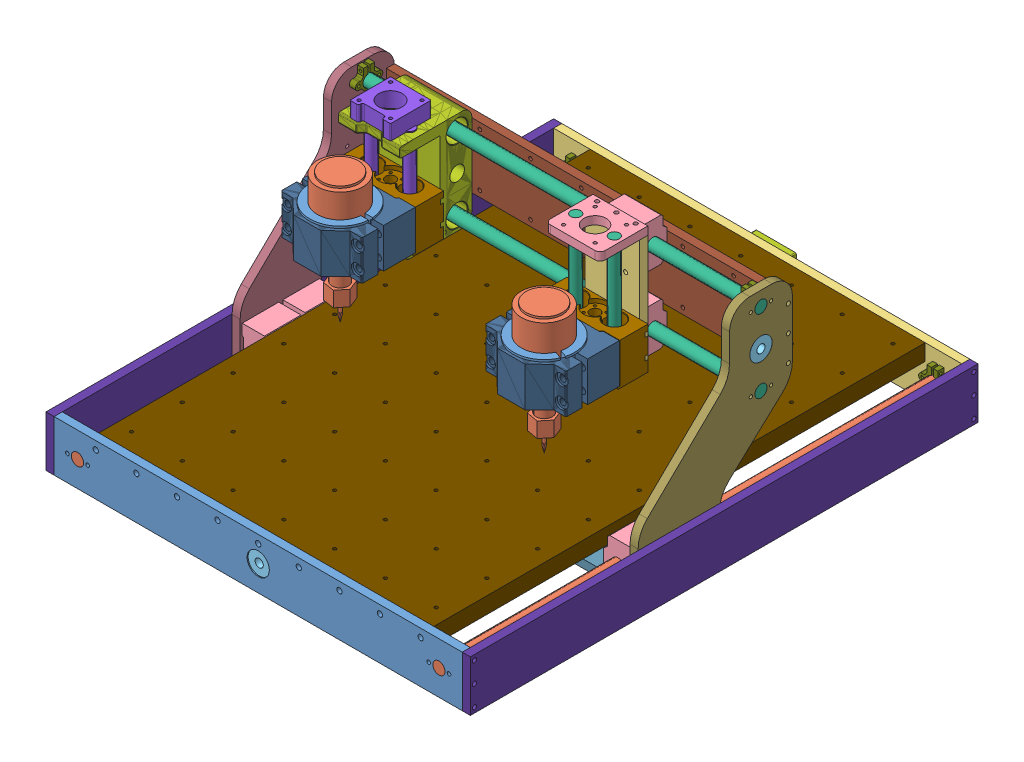
SolidWorks assembly Assem, configuration Default. Lengths in mm.
Overall size (419 226.21 510).
50 component instances, 26 part files, 97 mates.
Components (placement in the parent):
- front-1: front [Default] at (72.2728 169.5305 371.325) size (402 50 8)
- 12x500mm-1: 12x500mm [Default] at (-105.7272 169.5305 -120.675) x (-0.181171 0.983452 0) z (0 0 1) size (12 12 500)
- 12x500mm-2: 12x500mm [Default] at (250.2728 169.5305 -120.675) size (12 12 500)
- back-1: back [Default] at (72.2728 169.5305 -120.675) size (402 50 8)
- scs12uu-1: scs12uu [Default] at (-105.7272 169.5305 167.0973) x (0 -1 0) z (0 0 1) size (42 28 36)
- scs12uu-2: scs12uu [Default] at (250.2728 169.5305 167.0973) x (0 1 0) z (0 0 1) size (42 28 36)
- scs12uu-3: scs12uu [Default] at (-105.7272 169.5305 127.0973) x (0 -1 0) z (0 0 1) size (42 28 36)
- scs12uu-4: scs12uu [Default] at (250.2728 169.5305 127.0973) x (0 1 0) z (0 0 1) size (42 28 36)
- 608zz-1: 608zz [Default] at (72.2728 169.5305 371.325) size (21.9 21.9 7)
- 12x400mm-1: 12x400mm [Default] at (-127.7272 341.1948 84.0973) x (0 0 -1) z (1 0 0) size (12 12 400)
- 12x400mm-2: 12x400mm [Default] at (-127.7272 269.2548 84.0973) x (0 -0.924695 -0.380708) z (1 0 0) size (12 12 400)
- X_Carriage-1: X_Carriage [По умолчанию] at (-27.0136 255.7399 69.5893) x (0 1 0) z (0 0 1) size (100 60 71.3)
- 10x100mm-1: 10x100mm [Default] at (-76.0136 356.7399 119.6893) x (0.002971 0 0.999996) z (0 -1 0) size (10 10 100)
- 10x100mm-2: 10x100mm [Default] at (-38.0136 356.7399 119.6893) x (1 0 0) z (0 -1 0) size (10 10 100)
- Z_Carriage-1: Z_Carriage [По умолчанию] at (-96.2546 270.9801 89.6896) size (80 41 30.36)
- Z_Carriage2-1: Z_Carriage2 [По умолчанию] at (-96.2546 269.4801 89.6646) size (80 39 66.5)
- x_boss-1: x_boss [Default] at (72.2728 304.9298 53.0868) size (384 64 8)
- 608zz-2: 608zz [Default] at (265.2728 305.2248 84.0973) x (0 -0.443087 -0.896479) z (1 0 0) size (21.9 21.9 7)
- right-2: right [Default] at (264.2728 241.8465 141.4627) x (0 0 -1) z (1 0 0) size (152 207.66 8)
- left-2: left [Default] at (-127.7272 241.8563 141.4386) x (0 0 -1) z (1 0 0) size (152 207.66 8)
- y_boss-1: y_boss [Default] at (72.2728 158.2805 165.0973) x (1 0 0) z (0 -1 0) size (336 78 8)
- y_boss2-1: y_boss2 [Default] at (72.2728 177.2805 165.0973) x (1 0 0) z (0 -1 0) size (60 60 19)
- l12mm_holder-1: l12mm_holder [Default] at (-105.7272 169.5305 365.325) size (27 20.92 6)
- l12mm_holder-2: l12mm_holder [Default] at (250.2728 169.5305 365.325) size (27 20.92 6)
- l12mm_holder-3: l12mm_holder [Default] at (250.2728 169.5305 -112.675) size (27 20.92 6)
- l12mm_holder-4: l12mm_holder [Default] at (-105.7272 169.5305 -112.675) size (27 20.92 6)
- l12mm_holder-5: l12mm_holder [Default] at (-119.7272 269.2548 84.0973) x (0 0 -1) z (1 0 0) size (27 20.92 6)
- l12mm_holder-6: l12mm_holder [Default] at (258.2728 341.1948 84.0973) x (0 0 -1) z (1 0 0) size (27 20.92 6)
- l12mm_holder-7: l12mm_holder [Default] at (258.2728 269.2548 84.0973) x (0 0 -1) z (1 0 0) size (27 20.92 6)
- l12mm_holder-8: l12mm_holder [Default] at (-119.7272 341.1948 84.0973) x (0 0 -1) z (1 0 0) size (27 20.92 6)
- side-1: side [Default] at (-136.7272 169.5305 129.325) x (0 0 -1) z (1 0 0) size (500 50 8)
- side-2: side [Default] at (273.2728 169.5305 129.325) x (0 0 -1) z (1 0 0) size (500 50 8)
- table-1: table [Default] at (72.2728 186.5305 -112.675) size (330 16 484)
- 775mot_holder-1: 775mot_holder [Default] at (-57.0136 271.9801 169.2982) x (1 0 0) z (0 1 0) size (59.93 60 37)
- SPINDEL-1: SPINDEL [Default] at (-57.0136 332.6508 169.2982) x (0.999846 0 -0.017553) z (0 -1 0) size (45 45 129)
- Assem1-1: Assem1 [Default] at (58.0268 229.0373 50.2513) size (80 169.79 141.21)
  - Part1-1: Part1 [Default] at (89.8174 75.2675 47.846) size (54 112 8)
  - Part2-1: Part2 [Default] at (89.8174 131.2675 72.846) x (1 0 0) z (0 1 0) size (54 47 8)
  - Part3-1: Part3 [Default] at (89.8174 19.2675 72.846) x (1 0 0) z (0 1 0) size (54 39 8)
  - scs12uu-1: scs12uu [Default] at (71.8174 40.2175 33.846) x (0 -1 0) z (1 0 0) size (42 28 36)
  - scs12uu-2: scs12uu [Default] at (71.8174 112.1575 33.846) x (0 -1 0) z (1 0 0) size (42 28 36)
  - 10x130mm-1: 10x130mm [Default] at (70.8174 139.2675 72.846) x (1 0 0) z (0 -1 0) size (10 10 120)
  - 10x130mm-2: 10x130mm [Default] at (108.8174 139.2675 72.846) x (1 0 0) z (0 -1 0) size (10 10 120)
  - Z_Carriage-1: Z_Carriage [По умолчанию] at (50.5733 32.4743 42.849) size (80 41 30.36)
  - Z_Carriage2-1: Z_Carriage2 [По умолчанию] at (50.5733 30.9743 43.324) size (80 39 66.5)
  - SPINDEL-1: SPINDEL [Default] at (89.8143 96.4743 122.9576) x (1 0 0) z (0 -1 0) size (45 45 129)
  - 775mot_holder-1: 775mot_holder [Default] at (89.8143 33.4743 122.9576) x (0.94582 0 0.324692) z (0 1 0) size (59.93 60 37)
- mot_disp_xy-1: mot_disp_xy [Default] at (72.2728 169.5305 -130.675) size (40 40 10)
- mot_disp_xy-2: mot_disp_xy [Default] at (-137.7272 305.2248 84.0973) x (0 0 -1) z (1 0 0) size (40 40 10)
- mot_disp_z-1: mot_disp_z [Default] at (-56.6915 370.7399 120.0114) x (1 0 0) z (0 -1 0) size (40 40 15)
Mates (geometry in assembly coordinates):
- Concentric5: concentric aligned: cylinder of 12x500mm-1 through (-105.7272 169.5305 379.325) axis (0 0 -1) radius 6; cylinder of scs12uu-1 through (-105.7272 169.5305 203.0973) axis (0 0 -1) radius 6
- Concentric6: concentric aligned: cylinder of 12x500mm-2 through (250.2728 169.5305 379.325) axis (0 0 -1) radius 6; cylinder of scs12uu-2 through (250.2728 169.5305 203.0973) axis (0 0 -1) radius 6
- Concentric7: concentric aligned: cylinder of 12x500mm-2 through (250.2728 169.5305 379.325) axis (0 0 -1) radius 6; cylinder of scs12uu-4 through (250.2728 169.5305 163.0973) axis (0 0 -1) radius 6
- Concentric8: concentric aligned: cylinder of 12x500mm-1 through (-105.7272 169.5305 379.325) axis (0 0 -1) radius 6; cylinder of scs12uu-3 through (-105.7272 169.5305 163.0973) axis (0 0 -1) radius 6
- Coincident7: coincident aligned: plane of scs12uu-2 through (262.7845 160.3139 203.0973) normal (1 0 0); plane of scs12uu-4 through (262.7845 160.3139 163.0973) normal (1 0 0)
- Coincident8: coincident aligned: plane of scs12uu-1 through (-118.2389 178.747 203.0973) normal (-1 0 0); plane of scs12uu-3 through (-118.2389 178.747 163.0973) normal (-1 0 0)
- Concentric18: concentric aligned: cylinder of X_Carriage-1 through (-76.0136 256.7399 119.6893) axis (0 1 0) radius 4.8; cylinder of 10x100mm-1 through (-76.0136 256.7399 119.6893) axis (0 1 0) radius 5
- Coincident14: coincident anti-aligned: plane of X_Carriage-1 through (-76.0136 256.7399 119.6893) normal (0 1 0); plane of 10x100mm-1 through (-76.0136 256.7399 119.6893) normal (0 -1 0)
- Concentric19: concentric aligned: cylinder of X_Carriage-1 through (-38.0136 256.7399 119.6893) axis (0 1 0) radius 4.8; cylinder of 10x100mm-2 through (-38.0136 256.7399 119.6893) axis (0 1 0) radius 5
- Coincident15: coincident anti-aligned: plane of X_Carriage-1 through (-38.0136 256.7399 119.6893) normal (0 1 0); plane of 10x100mm-2 through (-38.0136 256.7399 119.6893) normal (0 -1 0)
- Concentric20: concentric aligned: cylinder of 12x400mm-1 through (272.2728 341.1948 84.0973) axis (-1 0 0) radius 6; cylinder of X_Carriage-1 through (-27.0115 341.1948 84.0973) axis (-1 0 0) radius 10.5
- Coincident18: coincident anti-aligned: plane of Z_Carriage-1 through (-96.2546 270.9801 135.2982) normal (0 0 1); plane of Z_Carriage2-1 through (-96.2546 269.4801 135.2982) normal (0 0 -1)
- Concentric23: concentric aligned: cylinder of 10x100mm-2 through (-38.0136 256.7399 119.6893) axis (0 1 0) radius 5; cylinder of Z_Carriage-1 through (-38.0136 270.9801 119.6893) axis (0 1 0) radius 9.5
- Concentric28: concentric aligned: cylinder of 12x400mm-1 through (272.2728 341.1948 84.0973) axis (-1 0 0) radius 6; cylinder of right-2 through (272.2728 341.1948 84.0973) axis (-1 0 0) radius 6
- Concentric29: concentric anti-aligned: cylinder of scs12uu-4 through (236.2718 154.2805 132.0973) axis (1 0 0) radius 2; cylinder of right-2 through (272.2728 154.2805 132.0973) axis (-1 0 0) radius 2.1
- Concentric30: concentric anti-aligned: cylinder of scs12uu-2 through (236.2718 154.2805 198.0973) axis (1 0 0) radius 2; cylinder of right-2 through (272.2728 154.2805 198.0973) axis (-1 0 0) radius 2.1
- Coincident20: coincident anti-aligned: plane of scs12uu-2 through (264.2728 181.7236 203.0973) normal (1 0 0); plane of right-2 through (264.2728 279.4731 83.0973) normal (-1 0 0)
- Concentric31: concentric aligned: cylinder of x_boss-1 through (264.2738 330.3748 57.0868) axis (-1 0 0) radius 1.8; cylinder of right-2 through (272.2728 330.3748 57.0868) axis (-1 0 0) radius 2
- Parallel6: parallel aligned: plane of x_boss-1 through (72.2728 304.9298 53.0868) normal (0 0 -1); plane of right-2 through (272.2728 335.1948 53.0973) normal (0 0 -1)
- Concentric34: concentric aligned: cylinder of 12x400mm-1 through (272.2728 341.1948 84.0973) axis (-1 0 0) radius 6; cylinder of left-2 through (-119.7272 341.1948 84.0973) axis (-1 0 0) radius 6
- Concentric35: concentric aligned: cylinder of scs12uu-1 through (-91.7262 154.2805 198.0973) axis (-1 0 0) radius 2; cylinder of left-2 through (-119.7272 154.2805 198.0973) axis (-1 0 0) radius 2.1
- Concentric36: concentric aligned: cylinder of scs12uu-3 through (-91.7262 154.2805 132.0973) axis (-1 0 0) radius 2; cylinder of left-2 through (-119.7272 154.2805 132.0973) axis (-1 0 0) radius 2.1
- Coincident22: coincident anti-aligned: plane of scs12uu-1 through (-119.7272 181.7236 203.0973) normal (-1 0 0); plane of left-2 through (-119.7272 279.4829 83.0973) normal (1 0 0)
- Parallel7: parallel aligned: plane of x_boss-1 through (72.2728 304.9298 53.0868) normal (0 0 -1); plane of left-2 through (-119.7272 335.1948 53.0973) normal (0 0 -1)
- Concentric37: concentric aligned: cylinder of 12x400mm-2 through (272.2728 269.2548 84.0973) axis (-1 0 0) radius 6; cylinder of right-2 through (272.2728 269.2548 84.0973) axis (-1 0 0) radius 6
- Coincident24: coincident aligned: plane of 12x400mm-2 through (272.2728 269.2548 84.0973) normal (1 0 0); plane of right-2 through (272.2728 279.4731 83.0973) normal (1 0 0)
- Concentric38: concentric aligned: cylinder of 608zz-2 through (272.2728 305.2248 84.0973) axis (-1 0 0) radius 10.95; cylinder of right-2 through (272.2728 305.2248 84.0973) axis (-1 0 0) radius 11
- Coincident26: coincident aligned: plane of Z_Carriage-1 through (-17.0136 265.9791 143.5419) normal (1 0 0); plane of Z_Carriage2-1 through (-17.0136 267.9791 169.2982) normal (1 0 0)
- Parallel9: parallel aligned: plane of X_Carriage-1 through (-27.0136 255.7399 69.5893) normal (0 0 -1); plane of right-2 through (272.2728 335.1948 53.0973) normal (0 0 -1)
- Coincident27: coincident aligned: plane of 12x400mm-1 through (272.2728 341.1948 84.0973) normal (1 0 0); plane of right-2 through (272.2728 279.4731 83.0973) normal (1 0 0)
- Coincident28: coincident anti-aligned: plane of x_boss-1 through (264.2728 336.9298 61.0868) normal (1 0 0); plane of right-2 through (264.2728 279.4731 83.0973) normal (-1 0 0)
- Concentric41: concentric aligned: cylinder of front-1 through (250.2728 169.5305 379.325) axis (0 0 -1) radius 6; cylinder of 12x500mm-2 through (250.2728 169.5305 379.325) axis (0 0 -1) radius 6
- Concentric42: concentric aligned: cylinder of front-1 through (-105.7272 169.5305 379.325) axis (0 0 -1) radius 6; cylinder of 12x500mm-1 through (-105.7272 169.5305 379.325) axis (0 0 -1) radius 6
- Coincident29: coincident aligned: plane of front-1 through (72.2728 169.5305 379.325) normal (0 0 1); plane of 12x500mm-1 through (-105.7272 169.5305 379.325) normal (0 0 1)
- Coincident30: coincident aligned: plane of front-1 through (72.2728 169.5305 379.325) normal (0 0 1); plane of 12x500mm-2 through (250.2728 169.5305 379.325) normal (0 0 1)
- Concentric44: concentric aligned: cylinder of 12x500mm-1 through (-105.7272 169.5305 379.325) axis (0 0 -1) radius 6; cylinder of back-1 through (-105.7272 169.5305 -112.675) axis (0 0 -1) radius 6
- Coincident31: coincident aligned: plane of 12x500mm-1 through (-105.7272 169.5305 -120.675) normal (0 0 -1); plane of back-1 through (72.2728 169.5305 -120.675) normal (0 0 -1)
- Coincident32: coincident aligned: plane of 12x500mm-2 through (250.2728 169.5305 -120.675) normal (0 0 -1); plane of back-1 through (72.2728 169.5305 -120.675) normal (0 0 -1)
- Concentric51: concentric aligned: cylinder of y_boss-1 through (47.2728 150.2805 140.0973) axis (0 1 0) radius 2.1; cylinder of y_boss2-1 through (47.2728 158.2805 140.0973) axis (0 1 0) radius 2.2
- Concentric52: concentric aligned: cylinder of y_boss-1 through (97.2728 150.2805 190.0973) axis (0 1 0) radius 2.1; cylinder of y_boss2-1 through (97.2728 158.2805 190.0973) axis (0 1 0) radius 2.2
- Coincident36: coincident anti-aligned: plane of y_boss-1 through (72.2728 158.2805 165.0973) normal (0 1 0); plane of y_boss2-1 through (72.2728 158.2805 165.0973) normal (0 -1 0)
- Concentric59: concentric aligned: cylinder of scs12uu-4 through (236.2718 154.2805 132.0973) axis (1 0 0) radius 2; cylinder of y_boss-1 through (-95.7282 154.2805 132.0973) axis (1 0 0) radius 1.8
- Parallel14: parallel aligned: plane of scs12uu-4 through (264.2728 148.5305 163.0973) normal (0 -1 0); plane of y_boss-1 through (72.2728 150.2805 165.0973) normal (0 -1 0)
- Coincident38: coincident anti-aligned: plane of scs12uu-1 through (-95.7272 158.8256 203.0973) normal (1 0 0); plane of y_boss-1 through (-95.7272 150.2805 126.0973) normal (-1 0 0)
- Concentric69: concentric aligned: cylinder of front-1 through (-115.7272 169.5305 379.325) axis (0 0 -1) radius 1.8; cylinder of l12mm_holder-1 through (-115.7272 169.5305 371.325) axis (0 0 -1) radius 1.3
- Concentric70: concentric aligned: cylinder of front-1 through (-95.7272 169.5305 379.325) axis (0 0 -1) radius 1.8; cylinder of l12mm_holder-1 through (-95.7272 169.5305 371.325) axis (0 0 -1) radius 1.3
- Coincident43: coincident anti-aligned: plane of front-1 through (72.2728 169.5305 371.325) normal (0 0 -1); plane of l12mm_holder-1 through (-105.7272 169.5305 371.325) normal (0 0 1)
- Concentric71: concentric aligned: cylinder of front-1 through (240.2728 169.5305 379.325) axis (0 0 -1) radius 1.8; cylinder of l12mm_holder-2 through (240.2728 169.5305 371.325) axis (0 0 -1) radius 1.3
- Concentric72: concentric aligned: cylinder of front-1 through (260.2728 169.5305 379.325) axis (0 0 -1) radius 1.8; cylinder of l12mm_holder-2 through (260.2728 169.5305 371.325) axis (0 0 -1) radius 1.3
- Coincident44: coincident anti-aligned: plane of front-1 through (72.2728 169.5305 371.325) normal (0 0 -1); plane of l12mm_holder-2 through (250.2728 169.5305 371.325) normal (0 0 1)
- Concentric73: concentric aligned: cylinder of back-1 through (-115.7272 169.5305 -112.675) axis (0 0 -1) radius 1.8; cylinder of l12mm_holder-4 through (-115.7272 169.5305 -106.675) axis (0 0 -1) radius 1.3
- Concentric74: concentric aligned: cylinder of back-1 through (-95.7272 169.5305 -112.675) axis (0 0 -1) radius 1.8; cylinder of l12mm_holder-4 through (-95.7272 169.5305 -106.675) axis (0 0 -1) radius 1.3
- Coincident45: coincident anti-aligned: plane of back-1 through (72.2728 169.5305 -112.675) normal (0 0 1); plane of l12mm_holder-4 through (-105.7272 169.5305 -112.675) normal (0 0 -1)
- Concentric76: concentric aligned: cylinder of back-1 through (240.2728 169.5305 -112.675) axis (0 0 -1) radius 1.8; cylinder of l12mm_holder-3 through (240.2728 169.5305 -106.675) axis (0 0 -1) radius 1.3
- Concentric77: concentric aligned: cylinder of back-1 through (260.2728 169.5305 -112.675) axis (0 0 -1) radius 1.8; cylinder of l12mm_holder-3 through (260.2728 169.5305 -106.675) axis (0 0 -1) radius 1.3
- Coincident46: coincident anti-aligned: plane of back-1 through (72.2728 169.5305 -112.675) normal (0 0 1); plane of l12mm_holder-3 through (250.2728 169.5305 -112.675) normal (0 0 -1)
- Concentric78: concentric aligned: cylinder of left-2 through (-119.7272 341.1948 74.0973) axis (-1 0 0) radius 1.6; cylinder of l12mm_holder-8 through (-113.7272 341.1948 74.0973) axis (-1 0 0) radius 1.3
- Concentric79: concentric aligned: cylinder of left-2 through (-119.7272 341.1948 94.0973) axis (-1 0 0) radius 1.6; cylinder of l12mm_holder-8 through (-113.7272 341.1948 94.0973) axis (-1 0 0) radius 1.3
- Coincident47: coincident anti-aligned: plane of left-2 through (-119.7272 279.4829 83.0973) normal (1 0 0); plane of l12mm_holder-8 through (-119.7272 341.1948 84.0973) normal (-1 0 0)
- Concentric80: concentric aligned: cylinder of left-2 through (-119.7272 269.2548 74.0973) axis (-1 0 0) radius 1.6; cylinder of l12mm_holder-5 through (-113.7272 269.2548 74.0973) axis (-1 0 0) radius 1.3
- Parallel16: parallel aligned: cylinder of left-2 through (-119.7272 269.2548 94.0973) axis (-1 0 0) radius 1.6; cylinder of l12mm_holder-5 through (-113.7272 269.2548 94.0973) axis (-1 0 0) radius 1.3
- Coincident48: coincident anti-aligned: plane of left-2 through (-119.7272 279.4829 83.0973) normal (1 0 0); plane of l12mm_holder-5 through (-119.7272 269.2548 84.0973) normal (-1 0 0)
- Concentric84: concentric aligned: cylinder of right-2 through (272.2728 341.1948 74.0973) axis (-1 0 0) radius 1.6; cylinder of l12mm_holder-6 through (264.2728 341.1948 74.0973) axis (-1 0 0) radius 1.3
- Concentric85: concentric aligned: cylinder of right-2 through (272.2728 341.1948 94.0973) axis (-1 0 0) radius 1.6; cylinder of l12mm_holder-6 through (264.2728 341.1948 94.0973) axis (-1 0 0) radius 1.3
- Coincident50: coincident anti-aligned: plane of right-2 through (264.2728 279.4731 83.0973) normal (-1 0 0); plane of l12mm_holder-6 through (264.2728 341.1948 84.0973) normal (1 0 0)
- Concentric96: concentric aligned: cylinder of right-2 through (272.2728 269.2548 74.0973) axis (-1 0 0) radius 1.6; cylinder of l12mm_holder-7 through (264.2728 269.2548 74.0973) axis (-1 0 0) radius 1.3
- Concentric99: concentric aligned: cylinder of right-2 through (272.2728 269.2548 94.0973) axis (-1 0 0) radius 1.6; cylinder of l12mm_holder-7 through (264.2728 269.2548 94.0973) axis (-1 0 0) radius 1.3
- Coincident53: coincident anti-aligned: plane of right-2 through (264.2728 279.4731 83.0973) normal (-1 0 0); plane of l12mm_holder-7 through (264.2728 269.2548 84.0973) normal (1 0 0)
- Coincident54: coincident aligned: plane of front-1 through (72.2728 169.5305 371.325) normal (0 0 -1); plane of 608zz-1 through (72.2728 169.5305 371.325) normal (0 0 -1)
- Coincident55: coincident aligned: plane of Z_Carriage-1 through (-96.2546 306.9801 89.6896) normal (0 1 0); plane of Z_Carriage2-1 through (-96.2546 306.9801 89.6646) normal (0 1 0)
- Parallel17: parallel anti-aligned: plane of Z_Carriage-1 through (-96.2546 270.9801 107.4397) normal (0 0 -1); plane of x_boss-1 through (72.2728 304.9298 61.0868) normal (0 0 1)
- Concentric100: concentric aligned: cylinder of 12x500mm-2 through (250.2728 169.5305 379.325) axis (0 0 -1) radius 6; cylinder of back-1 through (250.2728 169.5305 -112.675) axis (0 0 -1) radius 6
- Coincident56: coincident anti-aligned: plane of front-1 through (-128.7272 144.5305 379.325) normal (-1 0 0); plane of side-1 through (-128.7272 169.5305 129.325) normal (1 0 0)
- Coincident57: coincident aligned: plane of front-1 through (72.2728 169.5305 379.325) normal (0 0 1); plane of side-1 through (-128.7272 194.5305 379.325) normal (0 0 1)
- Coincident58: coincident aligned: plane of front-1 through (-128.7272 194.5305 379.325) normal (0 1 0); plane of side-1 through (-128.7272 194.5305 379.325) normal (0 1 0)
- Coincident59: coincident anti-aligned: plane of front-1 through (273.2728 144.5305 379.325) normal (1 0 0); plane of side-2 through (273.2728 169.5305 129.325) normal (-1 0 0)
- Coincident60: coincident aligned: plane of front-1 through (-128.7272 194.5305 379.325) normal (0 1 0); plane of side-2 through (281.2728 194.5305 379.325) normal (0 1 0)
- Coincident61: coincident aligned: plane of front-1 through (72.2728 169.5305 379.325) normal (0 0 1); plane of side-2 through (281.2728 194.5305 379.325) normal (0 0 1)
- Coincident62: coincident aligned: plane of 608zz-2 through (272.2728 305.2248 84.0973) normal (1 0 0); plane of right-2 through (272.2728 279.4731 83.0973) normal (1 0 0)
- Concentric102: concentric anti-aligned: cylinder of Z_Carriage2-1 through (-57.0136 267.9791 169.2982) axis (0 1 0) radius 28; cylinder of 775mot_holder-1 through (-57.0136 306.9801 169.2982) axis (0 -1 0) radius 22.5
- Coincident64: coincident anti-aligned: plane of Z_Carriage2-1 through (-96.2546 306.9801 89.6646) normal (0 1 0); plane of 775mot_holder-1 through (-57.0136 306.9801 169.2982) normal (0 -1 0)
- Concentric103: concentric anti-aligned: cylinder of 775mot_holder-1 through (-57.0136 306.9801 169.2982) axis (0 -1 0) radius 22.5; cylinder of SPINDEL-1 through (-57.0136 265.6508 169.2982) axis (0 1 0) radius 22.5
- Lock1: lock: unknown of Z_Carriage2-1; unknown of SPINDEL-1
- Concentric104: concentric aligned: cylinder of 12x400mm-1 through (272.2728 341.1948 84.0973) axis (-1 0 0) radius 6; cylinder of Assem1-1/scs12uu-2 through (165.8442 341.1948 84.0973) axis (-1 0 0) radius 6
- Concentric105: concentric aligned: cylinder of 12x400mm-2 through (272.2728 269.2548 84.0973) axis (-1 0 0) radius 6; cylinder of Assem1-1/scs12uu-1 through (165.8442 269.2548 84.0973) axis (-1 0 0) radius 6
- Concentric106: concentric aligned: cylinder of back-1 through (232.2728 186.5305 -112.675) axis (0 0 -1) radius 2.6; cylinder of table-1 through (232.2728 186.5305 371.325) axis (0 0 -1) radius 2.1
- Concentric107: concentric aligned: cylinder of back-1 through (-87.7272 186.5305 -112.675) axis (0 0 -1) radius 2.6; cylinder of table-1 through (-87.7272 186.5305 371.325) axis (0 0 -1) radius 2.1
- Coincident65: coincident anti-aligned: plane of back-1 through (72.2728 169.5305 -112.675) normal (0 0 1); plane of table-1 through (72.2728 186.5305 -112.675) normal (0 0 -1)
- Concentric108: concentric aligned: cylinder of back-1 through (87.7728 185.0305 -112.675) axis (0 0 -1) radius 1.6; cylinder of mot_disp_xy-1 through (87.7728 185.0305 -120.675) axis (0 0 -1) radius 1.6
- Concentric109: concentric aligned: cylinder of back-1 through (56.7728 154.0305 -112.675) axis (0 0 -1) radius 1.6; cylinder of mot_disp_xy-1 through (56.7728 154.0305 -120.675) axis (0 0 -1) radius 1.6
- Coincident66: coincident anti-aligned: plane of back-1 through (72.2728 169.5305 -120.675) normal (0 0 -1); plane of mot_disp_xy-1 through (53.2728 150.5305 -120.675) normal (0 0 1)
- Concentric110: concentric aligned: cylinder of left-2 through (-119.7272 320.7248 68.5973) axis (-1 0 0) radius 1.6; cylinder of mot_disp_xy-2 through (-127.7272 320.7248 68.5973) axis (-1 0 0) radius 1.6
- Concentric111: concentric aligned: cylinder of left-2 through (-119.7272 289.7248 99.5973) axis (-1 0 0) radius 1.6; cylinder of mot_disp_xy-2 through (-127.7272 289.7248 99.5973) axis (-1 0 0) radius 1.6
- Coincident67: coincident anti-aligned: plane of left-2 through (-127.7272 279.4829 83.0973) normal (-1 0 0); plane of mot_disp_xy-2 through (-127.7272 286.2248 103.0973) normal (1 0 0)
- Coincident69: coincident anti-aligned: plane of 10x100mm-1 through (-76.0136 356.7399 119.6893) normal (0 1 0); plane of mot_disp_z-1 through (-54.5627 356.7399 120.1977) normal (0 -1 0)
- Tangent1: tangent anti-aligned: plane of X_Carriage-1 through (-30.6147 255.7399 110.749) normal (-0.087158 0 0.996194); cylinder of mot_disp_z-1 through (-56.6915 355.7399 120.0114) axis (0 1 0) radius 11.5
- Tangent2: tangent anti-aligned: plane of X_Carriage-1 through (-72.3001 255.7399 73.5513) normal (0.996195 0 -0.087154); cylinder of mot_disp_z-1 through (-56.6915 355.7399 120.0114) axis (0 1 0) radius 11.5
